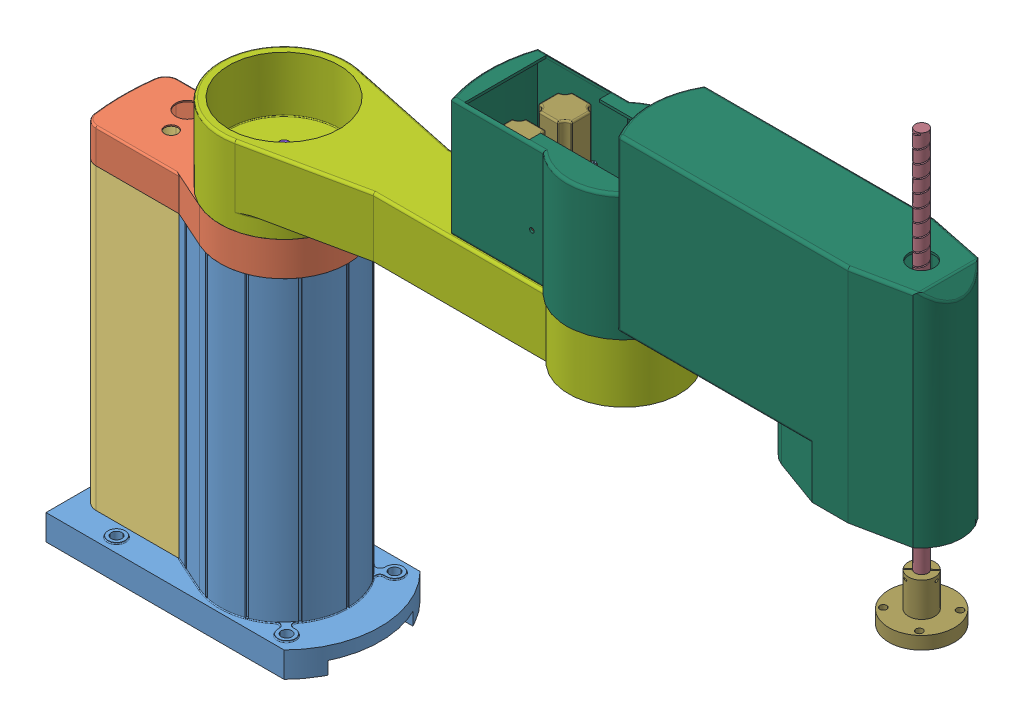
SolidWorks assembly complete_v1, configuration Default. Lengths in mm.
Overall size (1004.35 856.97 160).
129 component instances, 37 part files, 106 mates.
Components (placement in the parent):
- de-1: de [Default] at (-90.7503 19.9678 95.0449) size (313.14 421.07 160)
  - khau0_base-1: khau0_base [Default] at (129.1308 -0.2388 324.8346) size (313.14 381.07 160)
  - khau0_base_connector-1: khau0_base_connector [Default] at (274.1308 380.8312 324.8346) size (265 44.5 150)
  - khau0_base_support-1: khau0_base_support [Default] at (274.1308 29.7612 324.8346) size (115 351.07 97)
  - moto2-1: moto2 [Default] at (189.1308 317.8312 324.8346) size (46 90.12 46)
  - vit3.5-1: vit3.5 [Default] at (168.1308 383.8312 345.8346) x (0.949082 0 0.31503) z (0.31503 0 -0.949082) size (4.37 9.62 4.37)
  - vit3.5-2: vit3.5 [Default] at (168.1308 383.8312 303.8346) x (0.949082 0 -0.31503) z (-0.31503 0 -0.949082) size (4.37 9.62 4.37)
  - vit3.5-3: vit3.5 [Default] at (210.1308 383.8312 345.8346) x (-0.949082 0 0.31503) z (0.31503 0 0.949082) size (4.37 9.62 4.37)
  - vit3.5-4: vit3.5 [Default] at (210.1308 383.8312 303.8346) x (-0.949082 0 -0.31503) z (-0.31503 0 0.949082) size (4.37 9.62 4.37)
  - vit1-1: vit1 [Default] at (189.1308 372.771 268.3346) x (0.997762 0 -0.066868) z (0.066868 0 0.997762) size (13.68 33 13.68)
  - vit1-2: vit1 [Default] at (149.1792 372.771 284.883) x (0.658241 0 -0.752807) z (0.752807 0 0.658241) size (13.68 33 13.68)
  - vit1-3: vit1 [Default] at (132.6308 372.771 324.8346) x (-0.066868 0 -0.997762) z (0.997762 0 -0.066868) size (13.68 33 13.68)
  - vit1-4: vit1 [Default] at (149.1792 372.771 364.7861) x (-0.752807 0 -0.658241) z (0.658241 0 -0.752807) size (13.68 33 13.68)
  - vit1-5: vit1 [Default] at (189.1308 372.771 381.3346) x (-0.997762 0 0.066868) z (-0.066868 0 -0.997762) size (13.68 33 13.68)
  - vit1-6: vit1 [Default] at (229.0823 372.771 364.7861) x (-0.658241 0 0.752807) z (-0.752807 0 -0.658241) size (13.68 33 13.68)
  - vit1-7: vit1 [Default] at (245.6308 372.771 324.8346) x (0.066868 0 0.997762) z (-0.997762 0 0.066868) size (13.68 33 13.68)
  - vit1-8: vit1 [Default] at (229.0823 372.771 284.883) x (0.752807 0 0.658241) z (-0.658241 0 0.752807) size (13.68 33 13.68)
- khau1_arm-1: khau1_arm [Default] at (98.3805 462.799 419.8795) size (541 95 150)
- vitphi4-1: vitphi4 [Default] at (117.3805 463.4926 419.8795) x (-0.956538 0 0.291606) z (-0.291606 0 -0.956538) size (11.12 13.14 11.12)
- vitphi4-2: vitphi4 [Default] at (111.8155 463.4926 406.4444) x (-0.470178 0 0.882572) z (-0.882572 0 -0.470178) size (11.12 13.14 11.12)
- vitphi4-3: vitphi4 [Default] at (98.3805 463.4926 400.8795) x (0.291606 0 0.956538) z (-0.956538 0 0.291606) size (11.12 13.14 11.12)
- vitphi4-4: vitphi4 [Default] at (84.9455 463.4926 406.4444) x (0.882572 0 0.470178) z (-0.470178 0 0.882572) size (11.12 13.14 11.12)
- vitphi4-5: vitphi4 [Default] at (79.3805 463.4926 419.8795) x (0.956538 0 -0.291606) z (0.291606 0 0.956538) size (11.12 13.14 11.12)
- vitphi4-6: vitphi4 [Default] at (84.9455 463.4926 433.3145) x (0.470178 0 -0.882572) z (0.882572 0 0.470178) size (11.12 13.14 11.12)
- vitphi4-7: vitphi4 [Default] at (98.3805 463.4926 438.8795) x (-0.291606 0 -0.956538) z (0.956538 0 -0.291606) size (11.12 13.14 11.12)
- vitphi4-8: vitphi4 [Default] at (111.8155 463.4926 433.3145) x (-0.882572 0 -0.470178) z (0.470178 0 -0.882572) size (11.12 13.14 11.12)
- speed_reducer-1: speed_reducer [Default] at (498.3805 549.6751 419.8795) x (1 0 0) z (0 0 -1) size (125 40 125)
- vitphi6.2-1: vitphi6.2 [Default] at (498.3805 537.259 476.3795) x (0.999009 0 -0.044511) z (0.044511 0 0.999009) size (8.5 14.1 8.5)
- khau2_arm-1: khau2_arm [Default] at (498.3805 585.959 419.8795) size (546 115 125)
- moto2-1: moto2 [Default] at (498.3805 620.959 419.8795) x (1 0 0) z (0 0 -1) size (46 90.12 46)
- vit3.5-1: vit3.5 [Default] at (477.3805 554.959 440.8795) x (0.530664 0 -0.847582) z (0.847582 0 0.530664) size (4.37 9.62 4.37)
- vit3.5-2: vit3.5 [Default] at (519.3805 554.959 440.8795) x (0.530664 0 -0.847582) z (0.847582 0 0.530664) size (4.37 9.62 4.37)
- vit3.5-3: vit3.5 [Default] at (477.3805 554.959 398.8795) x (0.530664 0 -0.847582) z (0.847582 0 0.530664) size (4.37 9.62 4.37)
- vit3.5-4: vit3.5 [Default] at (519.3805 554.959 398.8795) x (0.530664 0 -0.847582) z (0.847582 0 0.530664) size (4.37 9.62 4.37)
- vitphi6.2-2: vitphi6.2 [Default] at (470.1305 537.259 468.8099) x (0.887422 0 0.460957) z (-0.460957 0 0.887422) size (8.5 14.1 8.5)
- vitphi6.2-3: vitphi6.2 [Default] at (449.4501 537.259 448.1295) x (0.538052 0 0.842912) z (-0.842912 0 0.538052) size (8.5 14.1 8.5)
- vitphi6.2-4: vitphi6.2 [Default] at (441.8805 537.259 419.8795) x (0.044511 0 0.999009) z (-0.999009 0 0.044511) size (8.5 14.1 8.5)
- vitphi6.2-5: vitphi6.2 [Default] at (449.4501 537.259 391.6295) x (-0.460957 0 0.887422) z (-0.887422 0 -0.460957) size (8.5 14.1 8.5)
- vitphi6.2-6: vitphi6.2 [Default] at (470.1305 537.259 370.949) x (-0.842912 0 0.538052) z (-0.538052 0 -0.842912) size (8.5 14.1 8.5)
- vitphi6.2-7: vitphi6.2 [Default] at (498.3805 537.259 363.3795) x (-0.999009 0 0.044511) z (-0.044511 0 -0.999009) size (8.5 14.1 8.5)
- vitphi6.2-8: vitphi6.2 [Default] at (526.6305 537.259 370.949) x (-0.887422 0 -0.460957) z (0.460957 0 -0.887422) size (8.5 14.1 8.5)
- vitphi6.2-9: vitphi6.2 [Default] at (547.3109 537.259 391.6295) x (-0.538052 0 -0.842912) z (0.842912 0 -0.538052) size (8.5 14.1 8.5)
- vitphi6.2-10: vitphi6.2 [Default] at (554.8805 537.259 419.8795) x (-0.044511 0 -0.999009) z (0.999009 0 -0.044511) size (8.5 14.1 8.5)
- vitphi6.2-11: vitphi6.2 [Default] at (547.3109 537.259 448.1295) x (0.460957 0 -0.887422) z (0.887422 0 0.460957) size (8.5 14.1 8.5)
- vitphi6.2-12: vitphi6.2 [Default] at (526.6305 537.259 468.8099) x (0.842912 0 -0.538052) z (0.538052 0 0.842912) size (8.5 14.1 8.5)
- end_effector-1: end_effector [Default] at (848.3805 371.6949 419.8795) x (0.662473 0 0.749086) z (-0.749086 0 0.662473) size (77 55 77)
- lead_screw-1: lead_screw [Default] at (848.3805 371.6949 419.8795) x (-0.587779 0 -0.809022) z (0.809022 0 -0.587779) size (50 505 50)
- khop3-1: khop3 [Default] at (848.3805 572.2726 419.8795) x (0.866025 0 0.5) z (-0.5 0 0.866025) size (50 50.6 50)
- pulykhop3_11-1: pulykhop3_11 [Default] at (848.3805 576.9945 419.8795) x (0.5 0 0.866025) z (-0.866025 0 0.5) size (34.5 16 34.5)
- banhdaikhop4-1: banhdaikhop4 [Default] at (848.3805 501.8436 419.8795) size (62 16 62)
- khop3-2: khop3 [Default] at (848.3805 504.7726 419.8795) x (0 0 1) z (-1 0 0) size (50 50.6 50)
- vitphi2.5l2-1: vitphi2.5l2 [Default] at (871.3805 597.9017 419.8795) x (1 0 0) z (0 0 -1) size (3.72 14.5 3.72)
- vitphi2.6dai12.5-1: vitphi2.6dai12.5 [Default] at (871.3805 530.959 419.8795) x (1 0 0) z (0 0 -1) size (4.82 13.85 4.82)
- vitphi2.6dai12.5-2: vitphi2.6dai12.5 [Default] at (859.8805 530.959 439.798) x (0.5 0 0.866025) z (0.866025 0 -0.5) size (4.82 13.85 4.82)
- vitphi2.6dai12.5-3: vitphi2.6dai12.5 [Default] at (836.8805 530.959 439.798) x (-0.5 0 0.866025) z (0.866025 0 0.5) size (4.82 13.85 4.82)
- vitphi2.6dai12.5-4: vitphi2.6dai12.5 [Default] at (825.3805 530.959 419.8795) x (-1 0 0) z (0 0 1) size (4.82 13.85 4.82)
- vitphi2.6dai12.5-5: vitphi2.6dai12.5 [Default] at (836.8805 530.959 399.9609) x (-0.5 0 -0.866025) z (-0.866025 0 0.5) size (4.82 13.85 4.82)
- vitphi2.6dai12.5-6: vitphi2.6dai12.5 [Default] at (859.8805 530.959 399.9609) x (0.5 0 -0.866025) z (-0.866025 0 -0.5) size (4.82 13.85 4.82)
- vitphi2.5l2-2: vitphi2.5l2 [Default] at (859.8805 597.9017 439.798) x (0.5 0 0.866025) z (0.866025 0 -0.5) size (3.72 14.5 3.72)
- vitphi2.5l2-3: vitphi2.5l2 [Default] at (836.8805 597.9017 439.798) x (-0.5 0 0.866025) z (0.866025 0 0.5) size (3.72 14.5 3.72)
- vitphi2.5l2-4: vitphi2.5l2 [Default] at (825.3805 597.9017 419.8795) x (-1 0 0) z (0 0 1) size (3.72 14.5 3.72)
- vitphi2.5l2-5: vitphi2.5l2 [Default] at (836.8805 597.9017 399.9609) x (-0.5 0 -0.866025) z (-0.866025 0 0.5) size (3.72 14.5 3.72)
- vitphi2.5l2-6: vitphi2.5l2 [Default] at (859.8805 597.9017 399.9609) x (0.5 0 -0.866025) z (-0.866025 0 -0.5) size (3.72 14.5 3.72)
- vitphi2.5l3-1: vitphi2.5l3 [Default] at (838.3112 579.4658 419.8795) x (1 0 0) z (0 0 -1) size (3.72 11.3 3.72)
- vitphi2.6-1: vitphi2.6 [Default] at (859.3805 517.2945 419.8795) x (1 0 0) z (0 0 -1) size (3.72 12.3 3.72)
- vitphi2.6-2: vitphi2.6 [Default] at (853.8805 517.2945 410.3532) x (0.5 0 -0.866025) z (-0.866025 0 -0.5) size (3.72 12.3 3.72)
- vitphi2.6-3: vitphi2.6 [Default] at (842.8805 517.2945 410.3532) x (-0.5 0 -0.866025) z (-0.866025 0 0.5) size (3.72 12.3 3.72)
- vitphi2.6-4: vitphi2.6 [Default] at (837.3805 517.2945 419.8795) x (-1 0 0) z (0 0 1) size (3.72 12.3 3.72)
- vitphi2.6-5: vitphi2.6 [Default] at (842.8805 517.2945 429.4057) x (-0.5 0 0.866025) z (0.866025 0 0.5) size (3.72 12.3 3.72)
- vitphi2.6-6: vitphi2.6 [Default] at (853.8805 517.2945 429.4057) x (0.5 0 0.866025) z (0.866025 0 -0.5) size (3.72 12.3 3.72)
- vitphi2.5l3-2: vitphi2.5l3 [Default] at (843.3459 579.4658 428.5997) x (0.5 0 -0.866025) z (-0.866025 0 -0.5) size (3.72 11.3 3.72)
- vitphi2.5l3-3: vitphi2.5l3 [Default] at (853.4151 579.4658 428.5997) x (-0.5 0 -0.866025) z (-0.866025 0 0.5) size (3.72 11.3 3.72)
- vitphi2.5l3-4: vitphi2.5l3 [Default] at (858.4498 579.4658 419.8795) x (-1 0 0) z (0 0 1) size (3.72 11.3 3.72)
- vitphi2.5l3-5: vitphi2.5l3 [Default] at (853.4151 579.4658 411.1592) x (-0.5 0 0.866025) z (0.866025 0 0.5) size (3.72 11.3 3.72)
- vitphi2.5l3-6: vitphi2.5l3 [Default] at (843.3459 579.4658 411.1592) x (0.5 0 0.866025) z (0.866025 0 -0.5) size (3.72 11.3 3.72)
- pulyphu18-1: pulyphu18 [Default] at (436.8605 569.159 392.9095) x (0.343817 0 -0.939037) z (0.939037 0 0.343817) size (10 16 10)
- vit3.5chopulyphu-1: vit3.5chopulyphu [Default] at (436.8605 576.159 392.9095) x (1 0 0) z (0 0 -1) size (4.94 8.65 4.94)
- pulyphu18-2: pulyphu18 [Default] at (436.8605 569.159 446.8495) x (0.343817 0 0.939037) z (-0.939037 0 0.343817) size (10 16 10)
- vit3.5chopulyphu-2: vit3.5chopulyphu [Default] at (436.8605 576.159 446.8495) x (1 0 0) z (0 0 -1) size (4.94 8.65 4.94)
- namgiuatruc-1: namgiuatruc [Default] at (721.4805 549.4971 419.8795) size (11.5 78 11.5)
- pulitructrunggian-1: pulitructrunggian [Default] at (721.4805 571.4511 419.8795) x (0.990289 0 -0.139027) z (0.139027 0 0.990289) size (16 16 16)
- tructrunggian-1: tructrunggian [Default] at (721.4805 554.6778 419.8795) x (-0.5 0 0.866025) z (-0.866025 0 -0.5) size (39 48 44.11)
- pulitructrunggian-2: pulitructrunggian [Default] at (721.4805 514.4669 419.8795) x (0.989579 0 -0.143988) z (-0.143988 0 -0.989579) size (16 16 16)
- vitphi2-1: vitphi2 [Default] at (721.4805 574.459 419.8795) size (2.94 9.5 2.94)
- vitphi2-2: vitphi2 [Default] at (721.4805 511.459 419.8795) x (0.652251 0 -0.758003) z (-0.758003 0 -0.652251) size (2.94 9.5 2.94)
- vitphi2-3: vitphi2 [Default] at (698.1805 527.959 419.8795) x (0.652251 0 -0.758003) z (-0.758003 0 -0.652251) size (2.94 9.5 2.94)
- vitphi2-4: vitphi2 [Default] at (733.1333 527.959 440.0595) x (0.652251 0 -0.758003) z (-0.758003 0 -0.652251) size (2.94 9.5 2.94)
- vitphi2-5: vitphi2 [Default] at (733.1333 527.959 399.6995) x (0.652251 0 -0.758003) z (-0.758003 0 -0.652251) size (2.94 9.5 2.94)
- pulyphu18-3: pulyphu18 [Default] at (640.7005 569.159 446.8495) x (0.343817 0 0.939037) z (-0.939037 0 0.343817) size (10 16 10)
- vit3.5chopulyphu-3: vit3.5chopulyphu [Default] at (640.7005 576.159 446.8495) x (1 0 0) z (0 0 -1) size (4.94 8.65 4.94)
- pulyphu-1: pulyphu [Default] at (705.8005 568.6149 446.8795) size (22 16 22)
- vitchung-1: vitchung [Default] at (705.8005 587.2269 446.8795) size (7.07 37.53 7.07)
- pulyphu18-4: pulyphu18 [Default] at (640.7005 569.159 392.9095) x (0.343817 0 -0.939037) z (0.939037 0 0.343817) size (10 16 10)
- pulyphu-2: pulyphu [Default] at (705.8005 568.6149 392.8795) size (22 16 22)
- vitchung-2: vitchung [Default] at (705.8005 587.2269 392.8795) x (-1 0 0) z (0 0 -1) size (7.07 37.53 7.07)
- vit3.5chopulyphu-4: vit3.5chopulyphu [Default] at (640.7005 576.159 392.9095) x (1 0 0) z (0 0 -1) size (4.94 8.65 4.94)
- matdemchuan-1: matdemchuan [Default] at (401.8605 593.959 392.9095) size (39 4 39)
- moto0-3: moto0 [Default] at (401.8605 660.959 392.9095) x (1 0 0) z (0 0 -1) size (39 76.12 39)
- pulykhau2-3: pulykhau2 [Default] at (401.8605 575.9382 392.9095) x (-0.746392 0 -0.665506) z (0.665506 0 -0.746392) size (22 16 22)
- vitdut-3: vitdut [Default] at (401.8605 588.459 392.9095) x (-0.976966 0 -0.213396) z (-0.213396 0 0.976966) size (5.5 7.5 5.5)
- vit3.5-13: vit3.5 [Default] at (384.8605 594.959 409.9095) x (0.530664 0 -0.847582) z (0.847582 0 0.530664) size (4.37 9.62 4.37)
- vit3.5-14: vit3.5 [Default] at (418.8605 594.959 409.9095) x (0.530664 0 -0.847582) z (0.847582 0 0.530664) size (4.37 9.62 4.37)
- vit3.5-15: vit3.5 [Default] at (384.8605 594.959 375.9095) x (0.530664 0 -0.847582) z (0.847582 0 0.530664) size (4.37 9.62 4.37)
- vit3.5-16: vit3.5 [Default] at (418.8605 594.959 375.9095) x (0.530664 0 -0.847582) z (0.847582 0 0.530664) size (4.37 9.62 4.37)
- vit3.5-17: vit3.5 [Default] at (391.8605 593.959 382.9095) x (0.612066 0 0.790806) z (0.790806 0 -0.612066) size (4.37 9.62 4.37)
- vit3.5-18: vit3.5 [Default] at (391.8605 593.959 402.9095) x (0.790806 0 -0.612066) z (-0.612066 0 -0.790806) size (4.37 9.62 4.37)
- vit3.5-19: vit3.5 [Default] at (411.8605 593.959 402.9095) x (-0.612066 0 -0.790806) z (-0.790806 0 0.612066) size (4.37 9.62 4.37)
- vit3.5-20: vit3.5 [Default] at (411.8605 593.959 382.9095) x (-0.790806 0 0.612066) z (0.612066 0 0.790806) size (4.37 9.62 4.37)
- moto0-4: moto0 [Default] at (401.8605 660.959 446.8495) x (1 0 0) z (0 0 -1) size (39 76.12 39)
- vit3.5-21: vit3.5 [Default] at (384.8605 594.959 429.8495) x (0.530664 0 0.847582) z (-0.847582 0 0.530664) size (4.37 9.62 4.37)
- vit3.5-22: vit3.5 [Default] at (418.8605 594.959 429.8495) x (0.530664 0 0.847582) z (-0.847582 0 0.530664) size (4.37 9.62 4.37)
- vit3.5-23: vit3.5 [Default] at (384.8605 594.959 463.8495) x (0.530664 0 0.847582) z (-0.847582 0 0.530664) size (4.37 9.62 4.37)
- vit3.5-24: vit3.5 [Default] at (418.8605 594.959 463.8495) x (0.530664 0 0.847582) z (-0.847582 0 0.530664) size (4.37 9.62 4.37)
- matdemchuan-2: matdemchuan [Default] at (401.8605 593.959 446.8495) size (39 4 39)
- pulykhau2-4: pulykhau2 [Default] at (401.8605 575.9382 446.8495) x (-0.746392 0 0.665506) z (-0.665506 0 -0.746392) size (22 16 22)
- vit3.5-25: vit3.5 [Default] at (391.8605 593.959 456.8495) x (0.612066 0 -0.790806) z (-0.790806 0 -0.612066) size (4.37 9.62 4.37)
- vit3.5-26: vit3.5 [Default] at (391.8605 593.959 436.8495) x (0.790806 0 0.612066) z (0.612066 0 -0.790806) size (4.37 9.62 4.37)
- vit3.5-27: vit3.5 [Default] at (411.8605 593.959 436.8495) x (-0.612066 0 0.790806) z (0.790806 0 0.612066) size (4.37 9.62 4.37)
- vit3.5-28: vit3.5 [Default] at (411.8605 593.959 456.8495) x (-0.790806 0 -0.612066) z (-0.612066 0 0.790806) size (4.37 9.62 4.37)
- vitdut-4: vitdut [Default] at (401.8605 588.459 446.8495) x (-0.976966 0 0.213396) z (0.213396 0 0.976966) size (5.5 7.5 5.5)
- khau2_cover-1: khau2_cover [Default] at (498.3805 541.6949 419.8795) size (557.5 270.16 135)
- vongbi-1: vongbi [Default] at (721.4805 563.959 419.8795) x (0.978486 0 -0.206314) z (0.206314 0 0.978486) size (13.6 3 13.6)
- vongbi-2: vongbi [Default] at (721.4805 518.959 419.8795) x (0.992648 0 -0.121037) z (0.121037 0 0.992648) size (13.6 3 13.6)
- speed_reducer-2: speed_reducer [Default] at (98.3805 419.5829 419.8795) size (125 40 125)
- vit3.5-29: vit3.5 [Default] at (640.7005 593.959 392.9095) size (4.37 9.62 4.37)
- vit3.5-30: vit3.5 [Default] at (640.7005 593.959 446.8495) size (4.37 9.62 4.37)
- belt1-1: belt1 [Default] at (401.8605 584.459 446.8495) x (1 0 0) z (0 0 -1) size (473.77 15 54.25)
- belt2-1: belt2 [Default] at (401.8605 584.459 392.9095) x (1 0 -0.000099) z (-0.000099 0 -1) size (337.62 15 45)
- belt34-1: belt34 [Default] at (721.4805 501.459 419.8795) size (164.9 15 61)
Mates (geometry in assembly coordinates):
- Concentric3: concentric aligned: cylinder of khau1_arm-1 through (117.3805 440.799 419.8795) axis (0 1 0) radius 4; cylinder of vitphi4-1 through (117.3805 470.5409 419.8795) axis (0 1 0) radius 4
- Coincident2: coincident anti-aligned: plane of khau1_arm-1 through (112.3805 469.299 419.8795) normal (0 1 0); plane of vitphi4-1 through (113.5543 469.299 421.0459) normal (0 -1 0)
- Concentric5: concentric aligned: cylinder of khau1_arm-1 through (498.3805 336.8244 419.8795) axis (0 1 0) radius 57.5; cylinder of speed_reducer-1 through (498.3805 549.6751 419.8795) axis (0 1 0) radius 51.5
- Coincident3: coincident anti-aligned: plane of khau1_arm-1 through (524.8805 506.459 419.8795) normal (0 1 0); plane of speed_reducer-1 through (505.8805 506.459 419.8795) normal (0 -1 0)
- Concentric11: concentric anti-aligned: cylinder of khau2_arm-1 through (498.3805 632.9123 419.8795) axis (0 -1 0) radius 26.5; cylinder of moto2-1 through (498.3805 562.959 419.8795) axis (0 1 0) radius 7
- Concentric12: concentric aligned: cylinder of khau2_arm-1 through (477.3805 552.959 440.8795) axis (0 1 0) radius 1.75; cylinder of moto2-1 through (477.3805 530.959 440.8795) axis (0 1 0) radius 1.75
- Coincident6: coincident anti-aligned: plane of khau2_arm-1 through (498.3805 557.959 419.8795) normal (0 1 0); plane of moto2-1 through (517.8805 557.959 419.8795) normal (0 -1 0)
- Concentric13: concentric aligned: cylinder of moto2-1 through (477.3805 530.959 440.8795) axis (0 1 0) radius 1.75; cylinder of vit3.5-1 through (477.3805 566.4999 440.8795) axis (0 1 0) radius 1.75
- Coincident7: coincident anti-aligned: plane of moto2-1 through (475.3805 562.959 442.8795) normal (0 1 0); plane of vit3.5-1 through (478.3092 562.959 439.3962) normal (0 -1 0)
- Concentric14: concentric aligned: cylinder of speed_reducer-1 through (498.3805 549.6751 419.8795) axis (0 1 0) radius 7.5; cylinder of moto2-1 through (498.3805 562.959 419.8795) axis (0 1 0) radius 7
- Coincident8: coincident anti-aligned: plane of speed_reducer-1 through (497.3805 536.8535 410.8795) normal (-1 0 0); plane of moto2-1 through (497.3805 545.959 413.8795) normal (1 0 0)
- Coincident9: coincident anti-aligned: plane of speed_reducer-1 through (560.8805 543.459 419.8795) normal (0 1 0); plane of khau2_arm-1 through (498.3805 543.459 419.8795) normal (0 -1 0)
- Concentric15: concentric aligned: cylinder of vitphi6.2-1 through (498.3805 537.259 476.3795) axis (0 -1 0) radius 3.1; cylinder of khau2_arm-1 through (498.3805 636.96 476.3795) axis (0 -1 0) radius 3
- Coincident10: coincident anti-aligned: plane of vitphi6.2-1 through (501.4774 549.459 476.2415) normal (0 -1 0); plane of khau2_arm-1 through (498.3805 549.459 419.8795) normal (0 1 0)
- Concentric19: concentric anti-aligned: cylinder of end_effector-1 through (848.3805 371.6949 419.8795) axis (0 -1 0) radius 15.5; cylinder of lead_screw-1 through (848.3805 876.6949 419.8795) axis (0 1 0) radius 7.5
- Coincident13: coincident anti-aligned: plane of end_effector-1 through (854.3428 378.6949 426.6212) normal (0 -1 0); plane of lead_screw-1 through (833.686 378.6949 399.6539) normal (0 1 0)
- Concentric20: concentric anti-aligned: cylinder of khau2_arm-1 through (848.3805 636.96 419.8795) axis (0 -1 0) radius 21; cylinder of lead_screw-1 through (848.3805 876.6949 419.8795) axis (0 1 0) radius 7.5
- Concentric21: concentric aligned: cylinder of khau2_arm-1 through (848.3805 636.96 419.8795) axis (0 -1 0) radius 21; cylinder of khop3-1 through (848.3805 572.2726 419.8795) axis (0 -1 0) radius 21
- Coincident14: coincident anti-aligned: plane of khau2_arm-1 through (848.3805 589.459 419.8795) normal (0 -1 0); plane of khop3-1 through (866.567 589.459 430.3795) normal (0 1 0)
- Concentric23: concentric aligned: cylinder of khau2_arm-1 through (848.3805 636.96 419.8795) axis (0 -1 0) radius 21; cylinder of khop3-2 through (848.3805 504.7726 419.8795) axis (0 -1 0) radius 21
- Coincident15: coincident anti-aligned: plane of khau2_arm-1 through (775.3454 521.959 444.2234) normal (0 -1 0); plane of khop3-2 through (848.3805 521.959 440.8795) normal (0 1 0)
- Concentric25: concentric aligned: cylinder of khop3-2 through (871.3805 511.959 419.8795) axis (0 1 0) radius 1.25; cylinder of vitphi2.6dai12.5-1 through (871.3805 530.959 419.8795) axis (0 1 0) radius 1.3
- Coincident16: coincident anti-aligned: plane of khop3-2 through (848.3805 518.459 444.8795) normal (0 -1 0); plane of vitphi2.6dai12.5-1 through (872.6805 518.459 419.8795) normal (0 1 0)
- Concentric26: concentric aligned: cylinder of khop3-1 through (871.3805 579.459 419.8795) axis (0 1 0) radius 1.25; cylinder of vitphi2.5l2-1 through (871.3805 599.459 419.8795) axis (0 1 0) radius 1.3
- Coincident17: coincident anti-aligned: plane of khop3-1 through (870.0311 585.959 432.3795) normal (0 -1 0); plane of vitphi2.5l2-1 through (872.6805 585.959 419.8795) normal (0 1 0)
- Concentric27: concentric anti-aligned: cylinder of khop3-1 through (848.3805 572.2726 419.8795) axis (0 -1 0) radius 7.5; cylinder of pulykhop3_11-1 through (848.3805 569.4945 419.8795) axis (0 1 0) radius 8
- Concentric28: concentric aligned: cylinder of khop3-1 through (853.8805 574.7895 429.4057) axis (0 1 0) radius 1.25; cylinder of pulykhop3_11-1 through (853.8805 569.4945 429.4057) axis (0 1 0) radius 1.25
- Coincident18: coincident anti-aligned: plane of khop3-1 through (861.3709 579.4945 427.3795) normal (0 -1 0); plane of pulykhop3_11-1 through (855.8805 579.4945 432.8698) normal (0 1 0)
- Concentric29: concentric anti-aligned: cylinder of banhdaikhop4-1 through (848.3805 496.9945 419.8795) axis (0 1 0) radius 8; cylinder of khop3-2 through (848.3805 504.7726 419.8795) axis (0 -1 0) radius 7.5
- Concentric30: concentric aligned: cylinder of banhdaikhop4-1 through (853.8805 496.9945 429.4057) axis (0 1 0) radius 1.25; cylinder of khop3-2 through (853.8805 507.2895 429.4057) axis (0 1 0) radius 1.25
- Coincident19: coincident anti-aligned: plane of banhdaikhop4-1 through (848.3805 511.9945 419.8795) normal (0 1 0); plane of khop3-2 through (848.3805 511.9945 434.8795) normal (0 -1 0)
- Concentric31: concentric aligned: cylinder of banhdaikhop4-1 through (859.3805 496.9945 419.8795) axis (0 1 0) radius 1.25; cylinder of vitphi2.6-1 through (859.3805 517.2945 419.8795) axis (0 1 0) radius 1.3
- Coincident20: coincident anti-aligned: plane of banhdaikhop4-1 through (848.3805 505.9945 419.8795) normal (0 -1 0); plane of vitphi2.6-1 through (860.6805 505.9945 419.8795) normal (0 1 0)
- Concentric32: concentric aligned: cylinder of pulykhop3_11-1 through (837.3805 569.4945 419.8795) axis (0 1 0) radius 1.25; cylinder of vitphi2.5l3-1 through (837.3805 584.7945 419.8795) axis (0 1 0) radius 1.3
- Coincident21: coincident anti-aligned: plane of pulykhop3_11-1 through (855.8805 574.4945 432.8698) normal (0 -1 0); plane of vitphi2.5l3-1 through (838.6805 574.4945 419.8795) normal (0 1 0)
- Concentric34: concentric anti-aligned: cylinder of khau2_arm-1 through (436.8605 569.159 392.9095) axis (0 1 0) radius 2.5; cylinder of pulyphu18-1 through (436.8605 569.159 392.9095) axis (0 -1 0) radius 2.5
- Coincident23: coincident aligned: plane of khau2_arm-1 through (436.8605 569.159 392.9095) normal (0 -1 0); plane of pulyphu18-1 through (437.72 569.159 390.5619) normal (0 -1 0)
- Concentric36: concentric anti-aligned: cylinder of khau2_arm-1 through (436.8605 636.96 392.9095) axis (0 -1 0) radius 1.75; cylinder of vit3.5chopulyphu-1 through (436.8605 576.159 392.9095) axis (0 1 0) radius 1.75
- Coincident25: coincident anti-aligned: plane of khau2_arm-1 through (436.8605 569.159 392.9095) normal (0 -1 0); plane of vit3.5chopulyphu-1 through (438.6105 569.159 392.9095) normal (0 1 0)
- Concentric37: concentric anti-aligned: cylinder of namgiuatruc-1 through (721.4805 577.959 419.8795) axis (0 1 0) radius 3.75; cylinder of pulitructrunggian-1 through (721.4805 571.4511 419.8795) axis (0 -1 0) radius 3.75
- Coincident26: coincident anti-aligned: plane of namgiuatruc-1 through (722.4805 581.959 419.8795) normal (0 1 0); plane of pulitructrunggian-1 through (725.1941 581.959 419.3581) normal (0 -1 0)
- Concentric38: concentric aligned: cylinder of namgiuatruc-1 through (721.4805 577.959 419.8795) axis (0 1 0) radius 3.75; cylinder of pulitructrunggian-2 through (721.4805 514.4669 419.8795) axis (0 1 0) radius 3.75
- Coincident27: coincident anti-aligned: plane of namgiuatruc-1 through (725.2305 503.959 419.8795) normal (0 -1 0); plane of pulitructrunggian-2 through (725.1914 503.959 419.3395) normal (0 1 0)
- Concentric40: concentric aligned: cylinder of pulitructrunggian-1 through (721.4805 571.4511 419.8795) axis (0 -1 0) radius 1; cylinder of vitphi2-1 through (721.4805 574.459 419.8795) axis (0 -1 0) radius 1.05
- Coincident28: coincident anti-aligned: plane of pulitructrunggian-1 through (722.9659 583.459 419.6709) normal (0 1 0); plane of vitphi2-1 through (722.5305 583.459 419.8795) normal (0 -1 0)
- Concentric41: concentric aligned: cylinder of pulitructrunggian-2 through (721.4805 514.4669 419.8795) axis (0 1 0) radius 1; cylinder of vitphi2-2 through (721.4805 511.459 419.8795) axis (0 1 0) radius 1.05
- Coincident29: coincident anti-aligned: plane of pulitructrunggian-2 through (722.9649 502.459 419.6635) normal (0 -1 0); plane of vitphi2-2 through (722.1654 502.459 419.0836) normal (0 1 0)
- Concentric42: concentric aligned: cylinder of namgiuatruc-1 through (721.4805 577.959 419.8795) axis (0 1 0) radius 5.75; cylinder of tructrunggian-1 through (721.4805 572.3965 419.8795) axis (0 1 0) radius 6
- Coincident30: coincident aligned: plane of namgiuatruc-1 through (727.2305 521.959 419.8795) normal (0 -1 0); plane of tructrunggian-1 through (718.4805 521.959 425.0756) normal (0 -1 0)
- Concentric45: concentric anti-aligned: cylinder of khau2_arm-1 through (698.1805 527.959 419.8795) axis (0 -1 0) radius 1; cylinder of tructrunggian-1 through (698.1805 518.959 419.8795) axis (0 1 0) radius 1
- Concentric46: concentric anti-aligned: cylinder of khau2_arm-1 through (733.1305 527.959 399.7011) axis (0 -1 0) radius 1; cylinder of tructrunggian-1 through (733.1305 518.959 399.7011) axis (0 1 0) radius 1
- Coincident32: coincident anti-aligned: plane of khau2_arm-1 through (775.3454 521.959 444.2234) normal (0 -1 0); plane of tructrunggian-1 through (732.4805 521.959 438.932) normal (0 1 0)
- Concentric47: concentric aligned: cylinder of tructrunggian-1 through (698.1805 518.959 419.8795) axis (0 1 0) radius 1; cylinder of vitphi2-3 through (698.1805 527.959 419.8795) axis (0 1 0) radius 1.05
- Coincident33: coincident anti-aligned: plane of tructrunggian-1 through (732.4805 518.959 438.932) normal (0 -1 0); plane of vitphi2-3 through (698.8654 518.959 419.0836) normal (0 1 0)
- Concentric48: concentric anti-aligned: cylinder of khau2_arm-1 through (640.7005 569.159 446.8495) axis (0 1 0) radius 2.5; cylinder of pulyphu18-3 through (640.7005 569.159 446.8495) axis (0 -1 0) radius 2.5
- Coincident34: coincident aligned: plane of khau2_arm-1 through (640.7005 569.159 446.8495) normal (0 -1 0); plane of pulyphu18-3 through (641.56 569.159 449.1971) normal (0 -1 0)
- Concentric49: concentric anti-aligned: cylinder of khau2_arm-1 through (640.7005 636.96 446.8495) axis (0 -1 0) radius 1.75; cylinder of vit3.5chopulyphu-3 through (640.7005 576.159 446.8495) axis (0 1 0) radius 1.75
- Coincident35: coincident anti-aligned: plane of khau2_arm-1 through (640.7005 569.159 446.8495) normal (0 -1 0); plane of vit3.5chopulyphu-3 through (642.4505 569.159 446.8495) normal (0 1 0)
- Concentric52: concentric anti-aligned: cylinder of khau2_arm-1 through (705.8005 569.159 446.8795) axis (0 1 0) radius 5; cylinder of pulyphu-1 through (705.8005 568.6149 446.8795) axis (0 -1 0) radius 5
- Coincident38: coincident aligned: plane of khau2_arm-1 through (705.8005 569.159 446.8795) normal (0 -1 0); plane of pulyphu-1 through (716.8005 569.159 446.8795) normal (0 -1 0)
- Concentric53: concentric aligned: cylinder of khau2_arm-1 through (705.8005 636.96 446.8795) axis (0 -1 0) radius 2.5; cylinder of vitchung-1 through (705.8005 587.2269 446.8795) axis (0 -1 0) radius 2.5
- Coincident39: coincident anti-aligned: plane of khau2_arm-1 through (705.8005 569.159 446.8795) normal (0 -1 0); plane of vitchung-1 through (708.3005 569.159 446.8795) normal (0 1 0)
- Concentric54: concentric aligned: cylinder of khau2_arm-1 through (391.8605 521.958 402.9095) axis (0 1 0) radius 1.75; cylinder of matdemchuan-1 through (391.8605 586.959 402.9095) axis (0 1 0) radius 1.75
- Concentric55: concentric aligned: cylinder of khau2_arm-1 through (391.8605 521.958 382.9095) axis (0 1 0) radius 1.75; cylinder of matdemchuan-1 through (391.8605 586.959 382.9095) axis (0 1 0) radius 1.75
- Coincident40: coincident anti-aligned: plane of khau2_arm-1 through (327.7347 593.959 186.9936) normal (0 1 0); plane of matdemchuan-1 through (401.8605 593.959 392.9095) normal (0 -1 0)
- Concentric56: concentric aligned: cylinder of matdemchuan-1 through (401.8605 593.958 392.9095) axis (0 1 0) radius 5; cylinder of moto0-3 through (401.8605 602.959 392.9095) axis (0 1 0) radius 5
- Concentric57: concentric anti-aligned: cylinder of matdemchuan-1 through (384.8605 597.959 375.9095) axis (0 -1 0) radius 1.75; cylinder of moto0-3 through (384.8605 584.959 375.9095) axis (0 1 0) radius 1.75
- Coincident41: coincident anti-aligned: plane of matdemchuan-1 through (401.8605 597.959 392.9095) normal (0 1 0); plane of moto0-3 through (417.8605 597.959 392.9095) normal (0 -1 0)
- Concentric58: concentric aligned: cylinder of moto0-3 through (384.8605 584.959 409.9095) axis (0 1 0) radius 1.75; cylinder of vit3.5-13 through (384.8605 606.4999 409.9095) axis (0 1 0) radius 1.75
- Coincident42: coincident anti-aligned: plane of moto0-3 through (382.3605 602.959 412.4095) normal (0 1 0); plane of vit3.5-13 through (385.7892 602.959 408.4262) normal (0 -1 0)
- Concentric59: concentric anti-aligned: cylinder of khau2_arm-1 through (391.8605 521.958 382.9095) axis (0 1 0) radius 1.75; cylinder of vit3.5-17 through (391.8605 582.4181 382.9095) axis (0 -1 0) radius 1.75
- Coincident43: coincident anti-aligned: plane of khau2_arm-1 through (498.3805 585.959 419.8795) normal (0 -1 0); plane of vit3.5-17 through (392.9316 585.959 384.2934) normal (0 1 0)
- Concentric60: concentric anti-aligned: cylinder of moto0-3 through (401.8605 602.959 392.9095) axis (0 1 0) radius 1.75; cylinder of pulykhau2-3 through (401.8605 575.9382 392.9095) axis (0 -1 0) radius 1.75
- Coincident44: coincident anti-aligned: plane of moto0-3 through (403.6105 584.959 392.9095) normal (0 -1 0); plane of pulykhau2-3 through (400.5543 584.959 391.7448) normal (0 1 0)
- Concentric61: concentric anti-aligned: cylinder of pulykhau2-3 through (401.8605 575.9382 392.9095) axis (0 -1 0) radius 1.75; cylinder of vitdut-3 through (401.8605 588.459 392.9095) axis (0 1 0) radius 1.75
- Coincident45: coincident anti-aligned: plane of pulykhau2-3 through (399.8079 582.459 391.0793) normal (0 -1 0); plane of vitdut-3 through (400.1508 582.459 392.536) normal (0 1 0)
- Concentric74: concentric aligned: cylinder of lead_screw-1 through (848.3805 876.6949 419.8795) axis (0 1 0) radius 7.5; cylinder of khau2_cover-1 through (848.3805 481.6949 419.8795) axis (0 1 0) radius 15
- Concentric75: concentric anti-aligned: cylinder of khau1_arm-1 through (498.3805 532.799 419.8795) axis (0 -1 0) radius 65; cylinder of khau2_cover-1 through (498.3805 801.6107 419.8795) axis (0 1 0) radius 66
- Concentric78: concentric aligned: cylinder of khau2_arm-1 through (440.8805 593.959 461.3795) axis (0 0 1) radius 1.75; cylinder of khau2_cover-1 through (440.8805 593.959 352.3795) axis (0 0 1) radius 2.75
- Concentric79: concentric anti-aligned: cylinder of namgiuatruc-1 through (721.4805 577.959 419.8795) axis (0 1 0) radius 4.25; cylinder of vongbi-2 through (721.4805 521.959 419.8795) axis (0 -1 0) radius 4.3
- Concentric82: concentric anti-aligned: cylinder of namgiuatruc-1 through (721.4805 577.959 419.8795) axis (0 1 0) radius 4.25; cylinder of vongbi-1 through (721.4805 566.959 419.8795) axis (0 -1 0) radius 4.3
- Coincident53: coincident aligned: plane of tructrunggian-1 through (732.4805 518.959 438.932) normal (0 -1 0); plane of vongbi-2 through (727.7342 518.959 419.1169) normal (0 -1 0)
- Coincident54: coincident aligned: plane of tructrunggian-1 through (715.9805 566.959 429.4057) normal (0 1 0); plane of vongbi-1 through (728.1342 566.959 418.4765) normal (0 1 0)
- Concentric83: concentric aligned: cylinder of khau2_arm-1 through (871.3805 521.959 419.8795) axis (0 1 0) radius 1.25; cylinder of vitphi2.5l2-1 through (871.3805 599.459 419.8795) axis (0 1 0) radius 1.3
- Concentric84: concentric aligned: cylinder of khau2_arm-1 through (871.3805 521.959 419.8795) axis (0 1 0) radius 1.25; cylinder of vitphi2.6dai12.5-1 through (871.3805 530.959 419.8795) axis (0 1 0) radius 1.3
- Concentric85: concentric aligned: circle of vitphi4-5; circle of speed_reducer-2
- Coincident56: coincident anti-aligned: plane of de-1/khau0_base_connector-1 through (98.3805 425.799 419.8795) normal (0 1 0); plane of speed_reducer-2 through (160.8805 425.799 419.8795) normal (0 -1 0)
- Concentric86: concentric aligned: circle of de-1/moto2-1; circle of speed_reducer-2
- Concentric87: concentric aligned: circle of vitphi4-1; circle of speed_reducer-2
- Coincident57: coincident anti-aligned: plane of de-1/khau0_base_connector-1 through (-74.4523 440.799 386.3795) normal (0 1 0); plane of khau1_arm-1 through (98.3805 440.799 419.8795) normal (0 -1 0)
- LimitAngle1: limit planar angle = 3.141593 rad anti-aligned: plane of de-1/khau0_base-1 through (38.3805 19.729 419.8795) normal (0 0 1); plane of khau1_arm-1 through (98.3805 462.799 419.8795) normal (0 0 1)
- LimitAngle2: limit planar angle = 3.141593 rad anti-aligned: plane of khau1_arm-1 through (98.3805 462.799 419.8795) normal (0 0 1); plane of khau2_arm-1 through (498.3805 585.959 419.8795) normal (0 0 1)
- Concentric88: concentric anti-aligned: circle of khau2_arm-1; circle of vit3.5-29
- Coincident60: coincident aligned: plane of khau2_arm-1 through (498.3805 601.959 419.8795) normal (0 1 0); circle of vit3.5-29
- Concentric89: concentric anti-aligned: circle of khau2_arm-1; circle of vit3.5-30
- Coincident61: coincident aligned: plane of khau2_arm-1 through (498.3805 601.959 419.8795) normal (0 1 0); circle of vit3.5-30
- LimitDistance2: limit distance = 100 mm aligned: plane of khau2_cover-1 through (878.3805 471.6949 419.8795) normal (0 -1 0); plane of end_effector-1 through (864.9423 371.6949 438.6066) normal (0 -1 0)
- Concentric94: concentric aligned: circle of pulykhau2-4; circle of belt1-1
- Coincident65: coincident aligned: plane of pulykhau2-4 through (393.6502 584.459 454.17) normal (0 -1 0); circle of belt1-1
- Concentric95: concentric anti-aligned: cylinder of pulyphu18-3 through (640.7005 569.159 446.8495) axis (0 -1 0) radius 5; circle of belt1-1
- Concentric96: concentric aligned: circle of pulykhau2-3; circle of belt2-1
- Coincident68: coincident anti-aligned: plane of pulykhau2-3 through (393.6502 584.459 385.5889) normal (0 -1 0); plane of belt2-1 through (640.7005 584.459 392.8859) normal (0 1 0)
- Concentric97: concentric aligned: circle of pulyphu-2; circle of belt2-1
- Concentric98: concentric aligned: circle of pulitructrunggian-2; circle of belt34-1
- Coincident70: coincident anti-aligned: plane of pulitructrunggian-2 through (728.4076 516.459 418.8716) normal (0 -1 0); plane of belt34-1 through (721.4805 516.459 419.8795) normal (0 1 0)
- Concentric104: concentric aligned: circle of banhdaikhop4-1; circle of belt34-1
